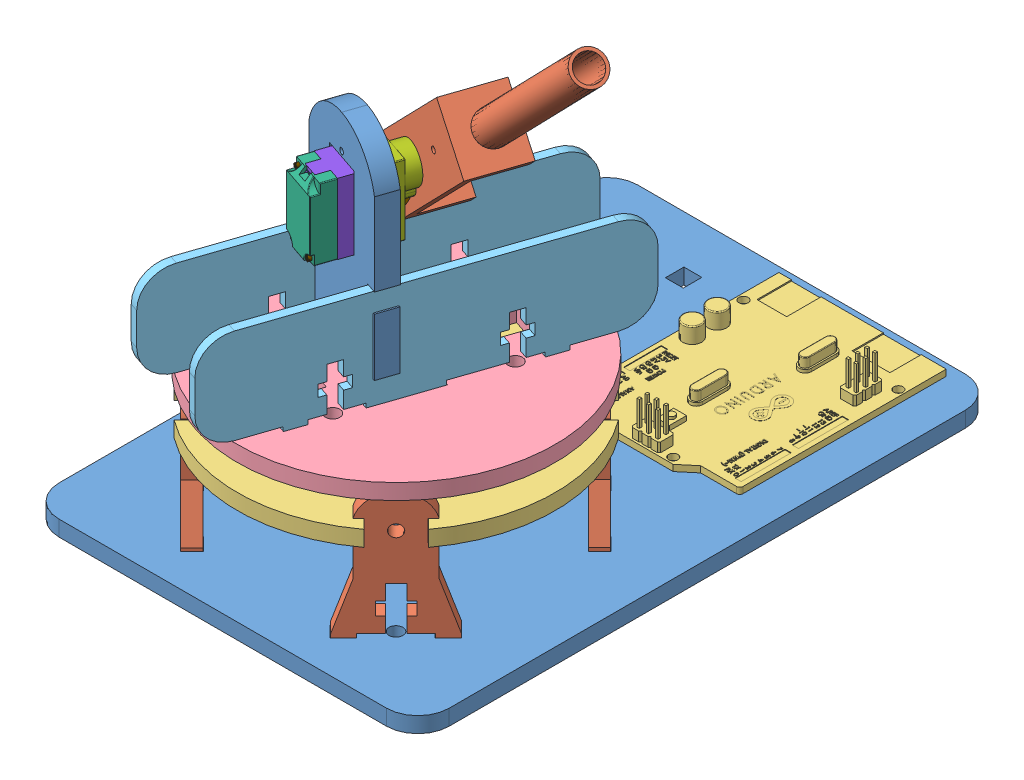
SolidWorks assembly Assem1, configuration Default. Lengths in mm.
Overall size (749.49 854.69 271.48).
52 component instances, 21 part files, 34 mates.
Components (placement in the parent):
- Base-1: Base [Default] at (-30.9709 79.5823 269.8456) x (0 0 -1) z (0 1 0) size (185 124.73 5)
- Column-1: Column [Default] at (50.6824 79.5823 267.5722) x (0.707107 0 0.707107) z (-0.707107 0 0.707107) size (29.66 44.62 5)
- Column-3: Column [Default] at (112.3988 79.5823 223.14) x (0.707107 0 -0.707107) z (0.707107 0 0.707107) size (29.66 44.62 5)
- Column-4: Column [Default] at (115.8028 79.5823 202.3302) x (0.707107 0 0.707107) z (-0.707107 0 0.707107) size (29.66 44.62 5)
- Column-5: Column [Default] at (47.1568 79.5823 158.0196) x (0.707107 0 -0.707107) z (0.707107 0 0.707107) size (29.66 44.62 5)
- Disc1-2: Disc1 [Default] at (153.8073 110.8913 224.4937) x (-0.707107 0 -0.707107) z (0 1 0) size (100.47 100.47 5)
- Disc2-1: Disc2 [Default] at (-22.6989 124.1994 122.5587) x (-0.321308 0 0.946975) z (0 1 0) size (101.54 101.54 5)
- ColumnServo2-1: ColumnServo2 [Default] at (105.7311 206.2578 119.8278) x (0 -1 0) z (0.946975 0 0.321308) size (36.56 116.79 2.8)
- ColumnServo2-2: ColumnServo2 [Default] at (77.6399 206.2578 110.2965) x (0 -1 0) z (0.946975 0 0.321308) size (36.56 116.79 2.8)
- MG90S-1: MG90S [Default] at (85.2901 143.0041 203.9675) x (-0.946975 0 -0.321308) z (0 -1 0) size (12 32.5 32)
  - Part1-1: Part1 [Default] at (21.0878 -43.0505 -32.5824) x (0 0 -1) z (1 0 0) size (22.54 9 12)
  - Part2-1: Part2 [Default] at (21.0878 -25.5505 -32.5824) x (0 0 -1) z (1 0 0) size (32 13 12)
  - Part3-1: Part3 [Default] at (21.0878 -36.0505 -32.5824) x (0 0 -1) z (1 0 0) size (22.5 16 12)
  - Motor_Body2-2: Motor_Body2 [Default] at (21.0878 -22.3005 -37.8324) x (0 -1 0) z (0.87496 0 0.484196) size (10 2 8)
  - Motor_Body2-3: Motor_Body2 [Default] at (21.0878 -19.8005 -31.3324) x (0 -1 0) z (0.109568 0 -0.993979) size (10 2 8)
  - Motor_Body2-6: Motor_Body2 [Default] at (21.0878 -19.8005 -37.8324) x (0 1 0) z (-0.993238 0 0.116099) size (10 2 8)
  - Motor_Body2-7: Motor_Body2 [Default] at (21.0878 -25.0505 -31.3324) x (0 1 0) z (0.977188 0 0.212376) size (10 2 8)
  - Motor_Body2-8: Motor_Body2 [Default] at (21.0878 -23.8005 -31.3324) x (0 1 0) z (0.977188 0 0.212376) size (10 2 8)
  - gear3-1: gear3 [Default] at (21.0878 -22.3005 -37.8324) x (0.87496 0 0.484196) z (-0.484196 0 0.87496) size (3.98 2.5 3.92)
  - gear1-2: gear1 [Default] at (21.0878 -19.8005 -31.3324) x (0.109568 0 -0.993979) z (0.993979 0 0.109568) size (3.96 2.5 3.87)
  - gear2-2: gear2 [Default] at (21.0878 -26.3005 -26.3324) x (0.891105 0 -0.453797) z (0.453797 0 0.891105) size (2.5 2.5 2.5)
  - Part4-1: Part4 [Default] at (21.0878 -17.0505 -37.8324) x (0.993238 0 -0.116099) z (0.116099 0 0.993238) size (4.5 6.5 4.5)
  - Motor_Body-1: Motor_Body [Default] at (21.0878 -26.5505 -26.3324) x (-1 0 0) z (0 0 1) size (10 14.25 8)
  - Motor_Body2-1: Motor_Body2 [Default] at (21.0878 -39.0505 -26.3324) size (10 2 8)
  - cilinder2-1: cilinder2 [Default] at (21.0878 -31.8005 -37.8324) x (0.116099 0 0.993238) z (-0.993238 0 0.116099) size (1.5 15 1.5)
  - cilinder1-1: cilinder1 [Default] at (21.0878 -27.3005 -31.3324) x (0.109568 0 -0.993979) z (0.993979 0 0.109568) size (1.25 12 1.25)
  - Part5-1: Part5 [Default] at (21.0878 -40.0505 -32.0824) x (0 0 -1) z (1 0 0) size (19.28 16 10.15)
  - Part6-1: Part6 [Default] at (16.5878 -42.0505 -22.8324) size (1.5 21 1.5)
  - Part6-2: Part6 [Default] at (25.5878 -40.5505 -42.3324) size (1.5 21 1.5)
- ColumnServo-1: ColumnServo [Default] at (16.5986 111.1242 207.6417) x (0.946975 0 0.321308) z (-0.321308 0 0.946975) size (33.54 69.69 6.5)
- holder-1: holder [Default] at (68.6263 172.4632 212.6227) x (-0.657932 0.719229 -0.223236) z (0.321308 0 -0.946975) size (685.24 428.81 20.5)
- Arduino board-1: Arduino board [Default] at (55.7596 84.5823 88.5151) x (0 0 1) z (-1 0 0) size (70 13 53.5)
- MG90S-2: MG90S [Default] at (97.1383 134.1917 235.6894) x (-0.000009 0 -1) z (1 0 -0.000009) size (12 32.5 32)
  - Part1-1: Part1 [Default] at (21.0878 -43.0505 -32.5824) x (0 0 -1) z (1 0 0) size (22.54 9 12)
  - Part2-1: Part2 [Default] at (21.0878 -25.5505 -32.5824) x (0 0 -1) z (1 0 0) size (32 13 12)
  - Part3-1: Part3 [Default] at (21.0878 -36.0505 -32.5824) x (0 0 -1) z (1 0 0) size (22.5 16 12)
  - Motor_Body2-2: Motor_Body2 [Default] at (21.0878 -22.3005 -37.8324) x (0 -1 0) z (0.87496 0 0.484196) size (10 2 8)
  - Motor_Body2-3: Motor_Body2 [Default] at (21.0878 -19.8005 -31.3324) x (0 -1 0) z (0.109568 0 -0.993979) size (10 2 8)
  - Motor_Body2-6: Motor_Body2 [Default] at (21.0878 -19.8005 -37.8324) x (0 1 0) z (-0.993238 0 0.116099) size (10 2 8)
  - Motor_Body2-7: Motor_Body2 [Default] at (21.0878 -25.0505 -31.3324) x (0 1 0) z (0.977188 0 0.212376) size (10 2 8)
  - Motor_Body2-8: Motor_Body2 [Default] at (21.0878 -23.8005 -31.3324) x (0 1 0) z (0.977188 0 0.212376) size (10 2 8)
  - gear3-1: gear3 [Default] at (21.0878 -22.3005 -37.8324) x (0.87496 0 0.484196) z (-0.484196 0 0.87496) size (3.98 2.5 3.92)
  - gear1-2: gear1 [Default] at (21.0878 -19.8005 -31.3324) x (0.109568 0 -0.993979) z (0.993979 0 0.109568) size (3.96 2.5 3.87)
  - gear2-2: gear2 [Default] at (21.0878 -26.3005 -26.3324) x (0.891105 0 -0.453797) z (0.453797 0 0.891105) size (2.5 2.5 2.5)
  - Part4-1: Part4 [Default] at (21.0878 -17.0505 -37.8324) x (0.993238 0 -0.116099) z (0.116099 0 0.993238) size (4.5 6.5 4.5)
  - Motor_Body-1: Motor_Body [Default] at (21.0878 -26.5505 -26.3324) x (-1 0 0) z (0 0 1) size (10 14.25 8)
  - Motor_Body2-1: Motor_Body2 [Default] at (21.0878 -39.0505 -26.3324) size (10 2 8)
  - cilinder2-1: cilinder2 [Default] at (21.0878 -31.8005 -37.8324) x (0.116099 0 0.993238) z (-0.993238 0 0.116099) size (1.5 15 1.5)
  - cilinder1-1: cilinder1 [Default] at (21.0878 -27.3005 -31.3324) x (0.109568 0 -0.993979) z (0.993979 0 0.109568) size (1.25 12 1.25)
  - Part5-1: Part5 [Default] at (21.0878 -40.0505 -32.0824) x (0 0 -1) z (1 0 0) size (19.28 16 10.15)
  - Part6-1: Part6 [Default] at (16.5878 -42.0505 -22.8324) size (1.5 21 1.5)
  - Part6-2: Part6 [Default] at (25.5878 -40.5505 -42.3324) size (1.5 21 1.5)
Mates (geometry in assembly coordinates):
- Coincident1: coincident anti-aligned: plane of Base-1 through (7.4569 84.5823 231.4178) normal (0.707107 0 -0.707107); plane of Column-1 through (47.1469 79.5823 271.1078) normal (-0.707107 0 0.707107)
- Coincident2: coincident aligned: plane of Base-1 through (-30.9709 79.5823 269.8456) normal (0 -1 0); plane of Column-1 through (47.1469 79.5823 271.1078) normal (0 -1 0)
- Coincident3: coincident anti-aligned: plane of Base-1 through (-19.762 84.5823 281.0545) normal (-0.707107 0 -0.707107); plane of Column-1 through (18.6658 79.5823 242.6267) normal (0.707107 0 0.707107)
- Coincident8: coincident anti-aligned: plane of Base-1 through (35.5857 84.5823 203.289) normal (-0.707107 0 0.707107); plane of Column-3 through (87.4533 79.5823 255.1566) normal (0.707107 0 -0.707107)
- Coincident9: coincident aligned: plane of Base-1 through (-30.9709 79.5823 269.8456) normal (0 -1 0); plane of Column-3 through (115.9343 79.5823 226.6755) normal (0 -1 0)
- Coincident13: coincident anti-aligned: plane of Base-1 through (72.6381 84.5823 166.2366) normal (0.707107 0 -0.707107); plane of Column-4 through (112.2673 79.5823 205.8658) normal (-0.707107 0 0.707107)
- Coincident14: coincident anti-aligned: plane of Base-1 through (-7.2321 84.5823 293.5844) normal (0.707107 0 0.707107); plane of Column-4 through (96.3769 79.5823 189.9754) normal (-0.707107 0 -0.707107)
- Coincident15: coincident aligned: plane of Base-1 through (-30.9709 79.5823 269.8456) normal (0 -1 0); plane of Column-4 through (112.2673 79.5823 205.8658) normal (0 -1 0)
- Coincident19: coincident anti-aligned: plane of Base-1 through (-44.2845 84.5823 256.532) normal (-0.707107 0 -0.707107); plane of Column-5 through (50.6923 79.5823 161.5551) normal (0.707107 0 0.707107)
- Coincident20: coincident anti-aligned: plane of Base-1 through (48.1156 84.5823 190.7591) normal (0.707107 0 -0.707107); plane of Column-5 through (34.802 79.5823 177.4455) normal (-0.707107 0 0.707107)
- Coincident21: coincident aligned: plane of Base-1 through (-30.9709 79.5823 269.8456) normal (0 -1 0); plane of Column-5 through (50.6923 79.5823 161.5551) normal (0 -1 0)
- Coincident31: coincident anti-aligned: plane of Base-1 through (20.8967 84.5823 321.7132) normal (-0.707107 0 -0.707107); plane of Column-3 through (115.9343 79.5823 226.6755) normal (0.707107 0 0.707107)
- Coincident32: coincident anti-aligned: plane of Column-5 through (23.4084 79.5823 188.8391) normal (-0.707107 0 0.707107); plane of Disc1-2 through (106.4351 115.8913 271.8658) normal (0.707107 0 -0.707107)
- Coincident34: coincident anti-aligned: plane of Column-4 through (112.2673 110.8913 205.8658) normal (0 1 0); plane of Disc1-2 through (153.8073 110.8913 224.4937) normal (0 -1 0)
- Distance1: distance = 0.381 mm anti-aligned: plane of Column-5 through (50.6923 79.5823 161.5551) normal (0.707107 0 0.707107); plane of Disc1-2 through (71.0499 115.8913 141.7364) normal (-0.707107 0 -0.707107)
- Coincident39: coincident anti-aligned: plane of Disc2-1 through (91.6412 129.1994 161.3542) normal (0.946975 0 0.321308); plane of ColumnServo2-1 through (56.4696 140.4074 265.014) normal (-0.946975 0 -0.321308)
- Coincident40: coincident anti-aligned: plane of Disc2-1 through (-32.7089 129.1994 152.0606) normal (0.321308 0 -0.946975); plane of ColumnServo2-1 through (84.2828 124.1994 191.7558) normal (-0.321308 0 0.946975)
- Coincident41: coincident aligned: plane of Disc2-1 through (59.5089 124.1994 214.563) normal (0 -1 0); plane of ColumnServo2-1 through (86.2778 124.1994 185.876) normal (0 -1 0)
- Coincident42: coincident anti-aligned: plane of Disc2-1 through (-32.7089 129.1994 152.0606) normal (0.321308 0 -0.946975); plane of ColumnServo2-2 through (56.1916 124.1994 182.2245) normal (-0.321308 0 0.946975)
- Coincident43: coincident anti-aligned: plane of Disc2-1 through (63.55 129.1994 151.8228) normal (0.946975 0 0.321308); plane of ColumnServo2-2 through (28.3784 140.4074 255.4826) normal (-0.946975 0 -0.321308)
- Coincident44: coincident aligned: plane of Disc2-1 through (59.5089 124.1994 214.563) normal (0 -1 0); plane of ColumnServo2-2 through (58.1866 124.1994 176.3447) normal (0 -1 0)
- Coincident45: coincident anti-aligned: plane of Column-5 through (50.6923 124.1994 161.5551) normal (0 1 0); plane of Disc2-1 through (59.5089 124.1994 214.563) normal (0 -1 0)
- Concentric1: concentric aligned: circle of Disc1-2; circle of Disc2-1
- Coincident46: coincident anti-aligned: plane of ColumnServo2-1 through (72.4616 154.718 226.5959) normal (-0.321308 0 0.946975); plane of ColumnServo-1 through (16.5986 111.1242 207.6417) normal (0.321308 0 -0.946975)
- Coincident47: coincident anti-aligned: plane of ColumnServo2-1 through (70.3308 136.374 232.8758) normal (0 1 0); plane of ColumnServo-1 through (14.5101 136.374 213.797) normal (0 -1 0)
- Distance2: distance = 0.254 mm anti-aligned: plane of ColumnServo-1 through (42.5224 111.1242 223.3016) normal (-0.946975 0 -0.321308); plane of ColumnServo2-2 through (31.0299 140.4074 256.3823) normal (0.946975 0 0.321308)
- Coincident50: coincident anti-aligned: plane of MG90S-1/Part2-1 through (57.1109 175.5865 221.3875) normal (-0.321308 0 0.946975); plane of ColumnServo-1 through (16.5986 111.1242 207.6417) normal (0.321308 0 -0.946975)
- Concentric2: concentric aligned: circle of MG90S-1/Part2-1; circle of ColumnServo-1
- Concentric3: concentric anti-aligned: circle of MG90S-1/Part2-1; circle of ColumnServo-1
- Concentric4: concentric aligned: circle of MG90S-1/Part4-1; circle of holder-1
- Coincident51: coincident aligned: plane of MG90S-1/Part4-1 through (61.9306 180.8365 207.1829) normal (0.321308 0 -0.946975); plane of holder-1 through (69.5902 172.4632 209.7818) normal (0.321308 0 -0.946975)
- Coincident52: coincident anti-aligned: plane of Base-1 through (-30.9709 84.5823 269.8456) normal (0 1 0); plane of Arduino board-1 through (108.2596 84.5823 153.5151) normal (0 -1 0)
- Parallel1: parallel aligned: plane of Base-1 through (121.6885 84.5823 269.8456) normal (1 0 0); plane of Arduino board-1 through (109.2596 86.5823 88.5151) normal (1 0 0)
- Coincident55: coincident anti-aligned: plane of Disc1-2 through (153.8073 110.8913 224.4937) normal (0 -1 0); plane of MG90S-2/Part2-1 through (64.5557 110.8913 214.602) normal (0 1 0)
